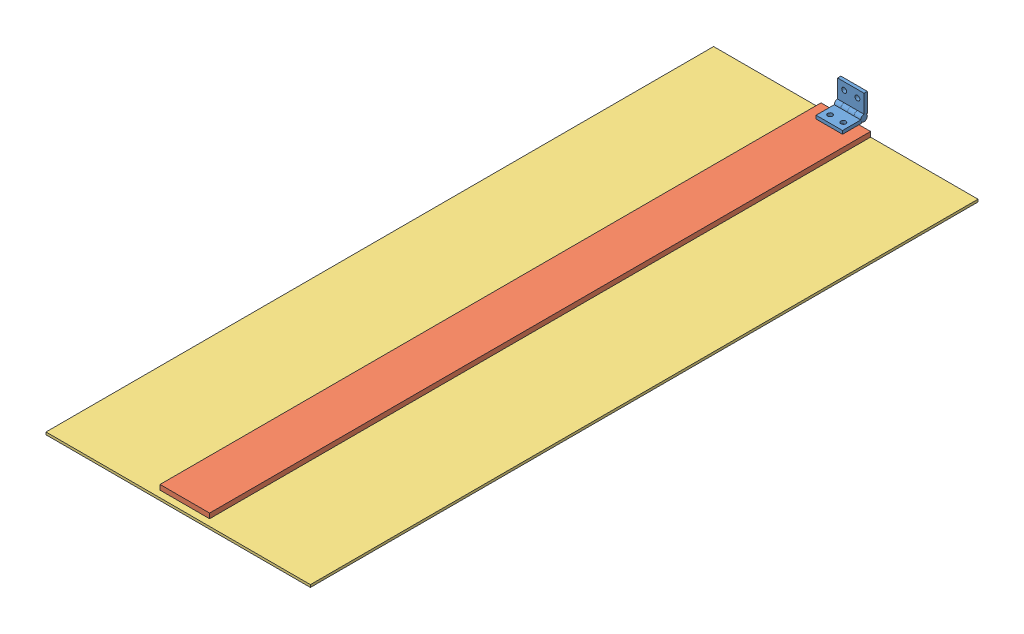
SolidWorks assembly door assembly, configuration Default. Lengths in mm.
Overall size (160 19.52 409.02).
4 component instances, 3 part files, 9 mates.
Components (placement in the parent):
- hinge part 2-1: hinge part 2 [Default] at (-145.8268 -10.0038 94.9276) x (1 0 0) z (0 1 0) size (16 15.02 4)
- hinge part 2-2: hinge part 2 [Default] at (-129.8268 5.0141 79.9097) x (-1 0 0) z (0 0 1) size (16 15.02 4)
- cargo door wood-1: cargo door wood [Default] at (-116.3106 -10.0038 172.1714) x (1 0 0) z (0 0 -1) size (30 3 400)
- cargo door-1: cargo door [Glass Fiber] at (-185.6142 -14.5038 284.8005) size (160 1.5 406.13)
Mates (geometry in assembly coordinates):
- Coincident1: coincident anti-aligned: line of hinge part 2-1 through (-133.8268 -8.0038 81.9097) axis (-1 0 0); line of hinge part 2-2 through (-133.8268 -8.0038 81.9097) axis (1 0 0)
- Coincident2: coincident aligned: plane of hinge part 2-1 through (-129.8268 -8.0038 94.9276) normal (1 0 0); plane of hinge part 2-2 through (-129.8268 5.0141 81.9097) normal (1 0 0)
- LimitAngle1: limit planar angle = 1.570796 rad anti-aligned: plane of hinge part 2-2 through (-129.8268 5.0141 79.9097) normal (0 0 -1); plane of hinge part 2-1 through (-145.8268 -10.0038 94.9276) normal (0 -1 0)
- Coincident4: coincident anti-aligned: plane of hinge part 2-1; plane of cargo door wood-1
- Distance1: distance = 10 mm anti-aligned: plane of cargo door wood-1 through (-152.8268 -13.0038 84.9276) normal (0 0 -1); plane of hinge part 2-1 through (-145.8268 -8.0038 94.9276) normal (0 0 1)
- Width1: width anti-aligned: plane of cargo door wood-1 through (-122.8268 -13.0038 484.9276) normal (1 0 0); plane of hinge part 2-1 through (-152.8268 -13.0038 484.9276) normal (-1 0 0); plane of cargo door wood-1 through (-145.8268 -8.0038 94.9276) normal (-1 0 0); plane of hinge part 2-1 through (-129.8268 -8.0038 94.9276) normal (1 0 0)
- Coincident6: coincident anti-aligned: plane of cargo door wood-1 through (-116.3106 -13.0038 172.1714) normal (0 -1 0); plane of cargo door-1 through (-185.6142 -13.0038 284.8005) normal (0 1 0)
- Width2: width anti-aligned: plane of cargo door-1 through (-57.8268 -13.0038 84.9276) normal (1 0 0); plane of cargo door wood-1 through (-217.8268 -13.0038 84.9276) normal (-1 0 0); plane of cargo door-1 through (-152.8268 -13.0038 484.9276) normal (-1 0 0); plane of cargo door wood-1 through (-122.8268 -13.0038 484.9276) normal (1 0 0)
- Coincident7: coincident aligned: plane of cargo door wood-1 through (-152.8268 -13.0038 84.9276) normal (0 0 -1); plane of cargo door-1 through (-217.8268 -13.0038 84.9276) normal (0 0 -1)
